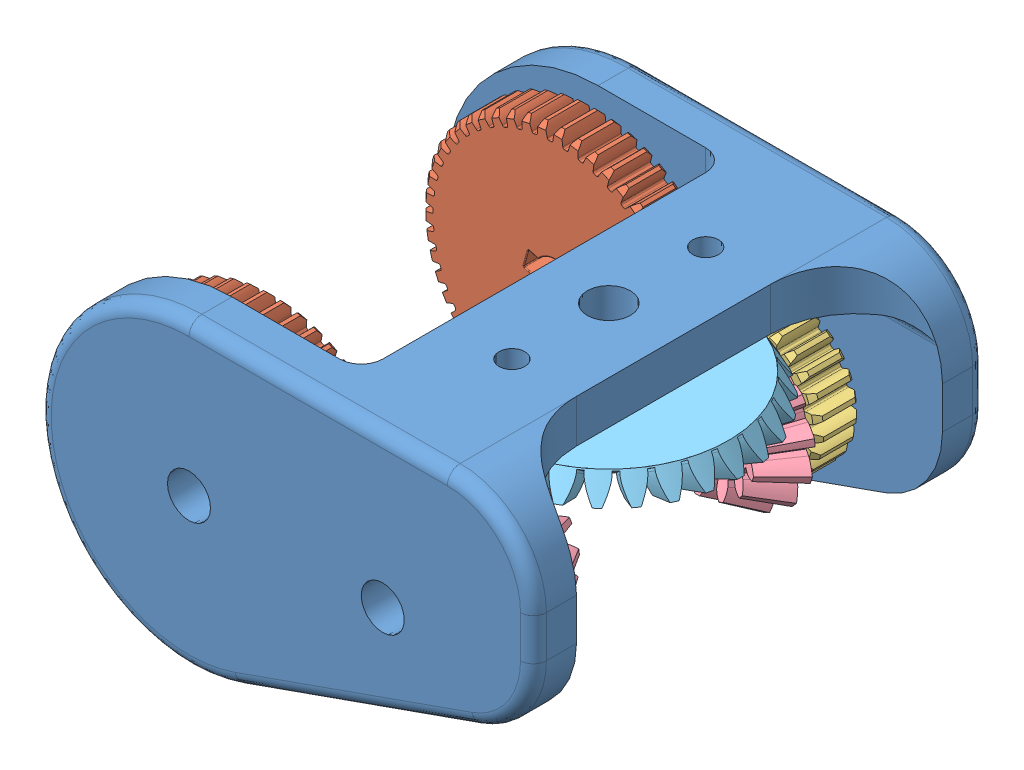
SolidWorks assembly ASSEMBLY Full Design 1st Attempt, configuration Default. Lengths in mm.
Overall size (131.76 113.01 105).
8 component instances, 5 part files, 19 mates.
Components (placement in the parent):
- Main Case-1: Main Case [Default] at (-4.7488 58.7631 49.9063) size (115 70 105)
- Secondary Big Spur Gear-1: Secondary Big Spur Gear [Default] at (-4.7488 58.7631 64.9063) x (0.270853 0.962621 0) z (0 0 1) size (62.4 62.32 10)
- Secondary Big Spur Gear-2: Secondary Big Spur Gear [Default] at (-4.7488 58.7631 139.9063) x (0.79228 -0.610157 0) z (0 0 1) size (62.4 62.32 10)
- Main Spur Gear - Copy-1: Main Spur Gear - Copy [Default] at (40.2512 58.7631 139.9063) x (0.255416 0.966831 0) z (0 0 1) size (32.38 32.33 10)
- Main Spur Gear - Copy-2: Main Spur Gear - Copy [Default] at (40.2512 58.7631 64.9063) x (-0.816258 -0.577688 0) z (0 0 1) size (32.38 32.33 10)
- Secondary Bevel Gear-1: Secondary Bevel Gear [Default] at (40.2512 58.7631 72.5284) x (0.816258 0.577688 0) z (0.577688 -0.816258 0) size (38.46 39.84 38.26)
- Secondary Bevel Gear-2: Secondary Bevel Gear [Default] at (40.2512 58.7631 132.2842) x (0.255416 0.966831 0) z (-0.966831 0.255416 0) size (38.46 39.84 38.26)
- Secondary Main Bevel Gear-1: Secondary Main Bevel Gear [Default] at (40.2512 76.0836 102.4063) x (0.561012 0 0.827808) z (0.827808 0 -0.561012) size (61.95 69.28 62)
Mates (geometry in assembly coordinates):
- Concentric1: concentric aligned: cylinder of Main Case-1 through (-4.7488 58.7631 144.9063) axis (0 0 1) radius 5; cylinder of Secondary Big Spur Gear-2 through (-4.7488 58.7631 134.9063) axis (0 0 1) radius 5
- Coincident1: coincident anti-aligned: plane of Main Case-1 through (-4.7488 58.7631 144.9063) normal (0 0 -1); plane of Secondary Big Spur Gear-2 through (-4.7488 58.7631 144.9063) normal (0 0 1)
- Concentric2: concentric anti-aligned: cylinder of Main Case-1 through (-4.7488 58.7631 59.9063) axis (0 0 -1) radius 5; cylinder of Secondary Big Spur Gear-1 through (-4.7488 58.7631 59.9063) axis (0 0 1) radius 5
- Coincident2: coincident anti-aligned: plane of Main Case-1 through (-4.7488 58.7631 59.9063) normal (0 0 1); plane of Secondary Big Spur Gear-1 through (-4.7488 58.7631 59.9063) normal (0 0 -1)
- Concentric3: concentric anti-aligned: cylinder of Main Case-1 through (40.2512 58.7631 59.9063) axis (0 0 -1) radius 5; cylinder of Main Spur Gear - Copy-2 through (40.2512 58.7631 59.9063) axis (0 0 1) radius 5
- Coincident3: coincident anti-aligned: plane of Main Case-1 through (-4.7488 58.7631 59.9063) normal (0 0 1); plane of Main Spur Gear - Copy-2 through (40.2512 58.7631 59.9063) normal (0 0 -1)
- GearMate1: gear = 60 : 30 mm: circle of Main Spur Gear - Copy-2; circle of Secondary Big Spur Gear-1
- Concentric5: concentric aligned: cylinder of Main Case-1 through (40.2512 58.7631 144.9063) axis (0 0 1) radius 5; cylinder of Main Spur Gear - Copy-1 through (40.2512 58.7631 134.9063) axis (0 0 1) radius 5
- Coincident4: coincident anti-aligned: plane of Main Case-1 through (-4.7488 58.7631 144.9063) normal (0 0 -1); plane of Main Spur Gear - Copy-1 through (40.2512 58.7631 144.9063) normal (0 0 1)
- GearMate2: gear = 60 : 30 mm: circle of Main Spur Gear - Copy-1; circle of Secondary Big Spur Gear-2
- Concentric7: concentric aligned: cylinder of Main Case-1 through (40.2512 58.7631 59.9063) axis (0 0 -1) radius 5; cylinder of Secondary Bevel Gear-1 through (40.2512 58.7631 81.9869) axis (0 0 -1) radius 5
- Coincident5: coincident aligned: plane of Main Spur Gear - Copy-2 through (45.9276 54.2047 59.9063) normal (-0.577688 0.816258 0); plane of Secondary Bevel Gear-1 through (42.6625 51.8939 81.9869) normal (-0.577688 0.816258 0)
- Concentric8: concentric aligned: cylinder of Main Spur Gear - Copy-1 through (40.2512 58.7631 134.9063) axis (0 0 1) radius 5; cylinder of Secondary Bevel Gear-2 through (40.2512 58.7631 122.8257) axis (0 0 1) radius 5
- Coincident6: coincident aligned: plane of Main Spur Gear - Copy-1 through (32.9726 58.6174 134.9063) normal (0.966831 -0.255416 0); plane of Secondary Bevel Gear-2 through (32.9726 58.6174 122.8257) normal (0.966831 -0.255416 0)
- Concentric9: concentric aligned: cylinder of Main Case-1 through (40.2512 23.7631 102.4063) axis (0 1 0) radius 5; cylinder of Secondary Main Bevel Gear-1 through (40.2512 69.8591 102.4063) axis (0 1 0) radius 5
- Coincident7: coincident: point of Secondary Bevel Gear-1; point of Secondary Main Bevel Gear-1
- Coincident8: coincident: line of Secondary Bevel Gear-2 through (40.2512 58.7631 102.4063) axis (-0.127708 -0.483416 0.866025)
- GearMate3: gear = 34.5 : 60 mm: circle of Secondary Main Bevel Gear-1; circle of Secondary Bevel Gear-1
- GearMate4: gear = 60 : 34.5 mm: circle of Secondary Bevel Gear-2; circle of Secondary Main Bevel Gear-1
